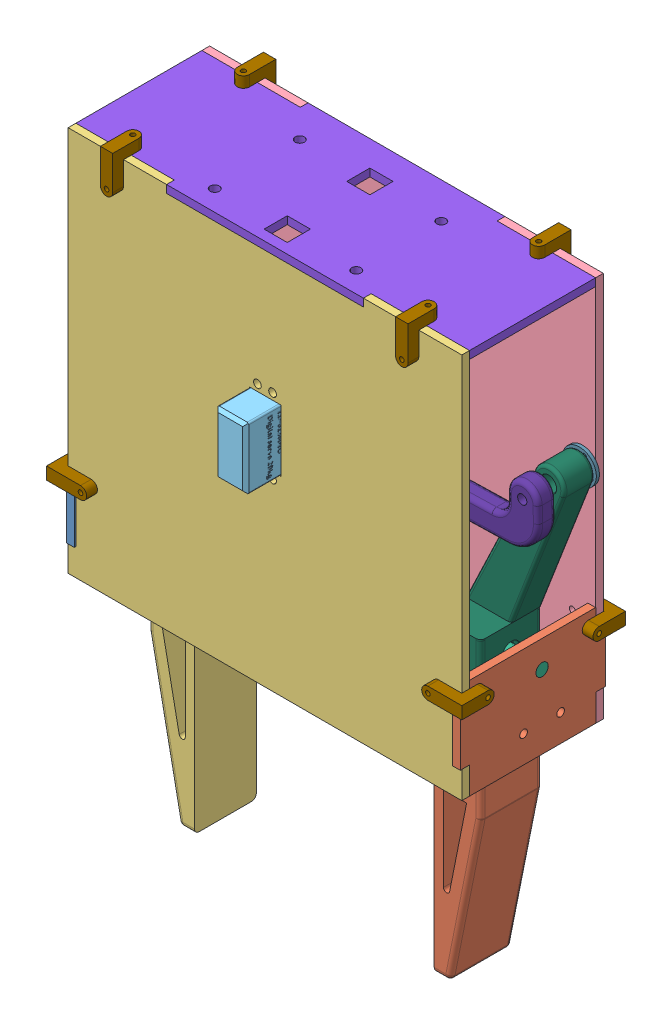
SolidWorks assembly Assem1_mica, configuration AltPosition_Default_1. Lengths in mm.
Overall size (292.18 394.5 121.5).
34 component instances, 21 part files, 82 mates.
Components (placement in the parent):
- Part2_mica-1: Part2_mica [Default] at (-23.3552 62.664 78.9474) x (0 0 -1) z (1 0 0)
- Part2_mica - Copy-1: Part2_mica - Copy [Default] at (231.6448 127.664 78.9474) x (0 0 -1) z (-1 0 0)
- Part1_mica-2: Part1_mica [Default] at (106.6448 187.664 100.9474)
- Part3_mica-1: Part3_mica [Default] at (-23.3552 127.664 19.3097) x (1 0 0) z (0 1 0)
- Servo 20 kg.stp-1: Servo 20 kg.stp [Default] at (114.1448 225.964 128.4474) x (1 0 0) z (0 1 0)
- Part3 - Copy-2: Part3 - Copy [Default] at (-18.3552 110.164 53.9474) x (1 0 0) z (0 -0.904123 0.427272)
- Part3-2: Part3 [Default] at (-23.3552 80.164 53.9474) x (1 0 0) z (0 0.470597 0.882348)
- Part4-1: Part4 [Default] at (-23.3552 307.664 100.9474) x (1 0 0) z (0 1 0)
- Part6-1: Part6 [Default] at (199.7698 312.664 14.3097) x (-1 0 0) z (0 0 -1)
- Part6-2: Part6 [Default] at (199.7698 312.664 105.9474)
- Part6-3: Part6 [Default] at (8.5198 312.664 14.3097) x (-1 0 0) z (0 0 -1)
- Part6-4: Part6 [Default] at (-23.3552 118.914 14.8917) x (0 -1 0) z (0 0 -1)
- Part6-5: Part6 [Default] at (-23.3552 118.914 105.9474) x (0 1 0) z (0 0 1)
- Part6-6: Part6 [Default] at (231.6448 118.914 13.9474) x (0 1 0) z (0 0 -1)
- Part6-7: Part6 [Default] at (231.6448 118.914 105.9474) x (0 -1 0) z (0 0 1)
- Part6-8: Part6 [Default] at (8.5198 312.664 105.9474)
- Part1-4: Part1 [Default] at (104.1448 216.164 83.9474) x (0.997708 -0.067666 0) z (0 0 -1)
- Part2 - Copy-2: Part2 - Copy [Default] at (226.6448 80.164 53.9474) x (0 0 -1) z (0 1 0) size (32 13 32)
- Part2-2: Part2 [Default] at (-18.3552 110.164 53.8656) x (0 -1 0) z (0 0 1) size (32 13 32)
- o-bi-1: o-bi [Default] at (235.7799 216.1762 62.9474) x (1 0 0) z (0 1 0) size (10 4 10)
- mat-bich-m3-1: mat-bich-m3 [Default] at (140.3117 213.7111 82.9474) x (0.997708 -0.067666 0) z (0.067666 0.997708 0) size (22 12 22)
- Part1.left - p1-2: Part1.left - p1 [Default] at (181.7677 50.164 53.9474) x (0 0 -1) z (0 1 0) size (40 64.01 185.34)
- Part1.right - p1-2: Part1.right - p1 [Default] at (26.5216 50.164 53.9474) x (0 0 1) z (0 1 0) size (40 64.01 184.7)
- Part4-3-2: Part4-3 [Default] at (235.7799 216.1762 70.9474) x (0.999667 0.025812 0) z (-0.025812 0.999667 0) size (115.5 12 40)
- Part4-3 - Copy-2: Part4-3 - Copy [Default] at (-27.4906 216.164 70.9474) x (-0.99967 -0.025685 0) z (0.025685 -0.99967 0) size (115.5 12 40)
- Part5-3: Part5 [Default] at (104.1448 216.164 80.9474) x (0.997708 -0.067666 0) z (0.067666 0.997708 0) size (92.5 10 20)
- Part1.left - p2-2: Part1.left - p2 [Default] at (181.7677 50.164 53.9474) x (0 0 -1) z (0 1 0) size (40 30 135.68)
- Part1.right - p2-2: Part1.right - p2 [Default] at (26.5216 50.164 53.9474) x (0 0 1) z (0 1 0) size (40 30 136.3)
- mat-bich-m3-2: mat-bich-m3 [Default] at (67.9779 218.6169 82.9474) x (-0.067666 -0.997708 0) z (0.997708 -0.067666 0) size (22 12 22)
- mat-bich-m3-3: mat-bich-m3 [Default] at (-27.4906 216.164 31.9474) x (0.918432 0.395578 0) z (0.395578 -0.918432 0) size (22 12 22)
- mat-bich-m3-4: mat-bich-m3 [Default] at (235.7799 216.1762 31.9474) x (0.395534 0.918452 0) z (0.918452 -0.395534 0) size (22 12 22)
- o-bi-2: o-bi [Default] at (140.3117 213.7111 67.9474) x (0.999998 0.001806 0) z (-0.001806 0.999998 0) size (10 4 10)
- o-bi-3: o-bi [Default] at (67.9779 218.6169 67.9474) x (0.530748 -0.84753 0) z (0.84753 0.530748 0) size (10 4 10)
- o-bi-4: o-bi [Default] at (-27.4906 216.164 62.9474) x (1 0 0) z (0 1 0) size (10 4 10)
Mates (geometry in assembly coordinates):
- Coincident4: coincident anti-aligned: plane of Part2_mica - Copy-1 through (226.6448 127.664 78.9474) normal (-1 0 0); plane of Part1_mica-2 through (226.6448 110.164 110.9474) normal (1 0 0)
- Coincident7: coincident anti-aligned: plane of Part2_mica - Copy-1 through (296.6525 62.664 100.9474) normal (0 0 1); plane of Part1_mica-2 through (106.6448 187.664 100.9474) normal (0 0 -1)
- Coincident10: coincident anti-aligned: plane of Part2_mica-1 through (-18.3552 62.664 78.9474) normal (1 0 0); plane of Part1_mica-2 through (-18.3552 187.664 110.9474) normal (-1 0 0)
- Coincident11: coincident aligned: plane of Part2_mica-1 through (-18.3552 62.664 78.9474) normal (0 -1 0); plane of Part1_mica-2 through (-23.3552 62.664 105.9474) normal (0 -1 0)
- Coincident12: coincident anti-aligned: plane of Part2_mica-1 through (46.6525 127.664 100.9474) normal (0 0 1); plane of Part1_mica-2 through (106.6448 187.664 100.9474) normal (0 0 -1)
- Concentric15: concentric aligned: cylinder of Part1_mica-2 through (109.0448 230.264 123.9474) axis (0 0 -1) radius 2.5; cylinder of Servo 20 kg.stp-1 through (109.0448 230.264 100.9474) axis (0 0 -1) radius 2.5
- Concentric16: concentric aligned: cylinder of Part1_mica-2 through (99.2448 230.264 123.9474) axis (0 0 -1) radius 2.5; cylinder of Servo 20 kg.stp-1 through (99.2448 230.264 100.9474) axis (0 0 -1) radius 2.5
- Coincident19: coincident anti-aligned: plane of Part1_mica-2 through (106.6448 187.664 100.9474) normal (0 0 -1); plane of Servo 20 kg.stp-1 through (104.1448 229.589 100.9474) normal (0 0 1)
- Coincident21: coincident anti-aligned: plane of Part2_mica - Copy-1 through (226.6448 127.664 78.9474) normal (-1 0 0); plane of Part3_mica-1 through (226.6448 110.164 24.3097) normal (1 0 0)
- Coincident24: coincident anti-aligned: plane of Part3_mica-1 through (104.1448 307.664 199.3097) normal (0 1 0); plane of Part4-1 through (-23.3552 307.664 100.9474) normal (0 -1 0)
- Coincident25: coincident anti-aligned: plane of Part1_mica-2 through (106.6448 187.664 100.9474) normal (0 0 -1); plane of Part4-1 through (-23.3552 312.664 100.9474) normal (0 0 1)
- Coincident26: coincident anti-aligned: plane of Part3_mica-1 through (40.3948 307.664 199.3097) normal (1 0 0); plane of Part4-1 through (40.3948 312.664 100.9474) normal (-1 0 0)
- Coincident27: coincident anti-aligned: plane of Servo 20 kg.stp-1 through (104.1448 216.164 86.9474) normal (0 0 -1); plane of Part1-4 through (104.1448 216.164 86.9474) normal (0 0 1)
- Concentric36: concentric aligned: cylinder of Servo 20 kg.stp-1 through (104.1448 216.164 86.9474) axis (0 0 -1) radius 3; cylinder of Part1-4 through (104.1448 216.164 86.9474) axis (0 0 -1) radius 3
- Coincident34: coincident anti-aligned: plane of Part1_mica-2 through (104.1448 307.664 285.9474) normal (0 1 0); plane of Part4-1 through (-23.3552 307.664 100.9474) normal (0 -1 0)
- Concentric60: concentric aligned: cylinder of Part4-1 through (8.5198 317.664 24.3097) axis (0 -1 0) radius 2; cylinder of Part6-3 through (8.5198 319.664 24.3097) axis (0 -1 0) radius 1.5
- Concentric61: concentric aligned: cylinder of Part4-1 through (199.7698 317.664 24.3097) axis (0 -1 0) radius 2; cylinder of Part6-1 through (199.7698 319.664 24.3097) axis (0 -1 0) radius 1.5
- Concentric62: concentric anti-aligned: cylinder of Part3_mica-1 through (199.7698 297.664 24.3097) axis (0 0 -1) radius 2; cylinder of Part6-1 through (199.7698 297.664 7.3097) axis (0 0 1) radius 1.5
- Coincident35: coincident anti-aligned: plane of Part3_mica-1 through (-23.3552 127.664 19.3097) normal (0 0 1); plane of Part4-1 through (-23.3552 307.664 19.3097) normal (0 0 -1)
- Concentric63: concentric anti-aligned: cylinder of Part3_mica-1 through (8.5198 297.664 24.3097) axis (0 0 -1) radius 2; cylinder of Part6-3 through (8.5198 297.664 7.3097) axis (0 0 1) radius 1.5
- Concentric64: concentric aligned: cylinder of Part4-1 through (8.5198 317.664 95.9474) axis (0 -1 0) radius 2; cylinder of Part6-8 through (8.5198 319.664 95.9474) axis (0 -1 0) radius 1.5
- Concentric65: concentric aligned: cylinder of Part1_mica-2 through (8.5198 297.664 110.9474) axis (0 0 -1) radius 2; cylinder of Part6-8 through (8.5198 297.664 112.9474) axis (0 0 -1) radius 1.5
- Concentric66: concentric aligned: cylinder of Part4-1 through (199.7698 317.664 95.9474) axis (0 -1 0) radius 2; cylinder of Part6-2 through (199.7698 319.664 95.9474) axis (0 -1 0) radius 1.5
- Concentric67: concentric aligned: cylinder of Part1_mica-2 through (199.7698 297.664 110.9474) axis (0 0 -1) radius 2; cylinder of Part6-2 through (199.7698 297.664 112.9474) axis (0 0 -1) radius 1.5
- Concentric68: concentric aligned: cylinder of Part2_mica-1 through (-28.3552 118.914 95.9474) axis (1 0 0) radius 2; cylinder of Part6-5 through (-30.3552 118.914 95.9474) axis (1 0 0) radius 1.5
- Concentric69: concentric aligned: cylinder of Part1_mica-2 through (-8.3552 118.914 110.9474) axis (0 0 -1) radius 2; cylinder of Part6-5 through (-8.3552 118.914 112.9474) axis (0 0 -1) radius 1.5
- Concentric70: concentric aligned: cylinder of Part2_mica-1 through (-28.3552 118.914 24.8917) axis (1 0 0) radius 2; cylinder of Part6-4 through (-30.3552 118.914 24.8917) axis (1 0 0) radius 1.5
- Concentric71: concentric anti-aligned: cylinder of Part3_mica-1 through (-8.3552 118.914 24.3097) axis (0 0 -1) radius 2; cylinder of Part6-4 through (-8.3552 118.914 7.8917) axis (0 0 1) radius 1.5
- Concentric72: concentric anti-aligned: cylinder of Part3_mica-1 through (216.6448 118.914 24.3097) axis (0 0 -1) radius 2; cylinder of Part6-6 through (216.6448 118.914 6.9474) axis (0 0 1) radius 1.5
- Concentric73: concentric aligned: cylinder of Part2_mica - Copy-1 through (236.6448 118.914 23.9474) axis (-1 0 0) radius 2; cylinder of Part6-6 through (238.6448 118.914 23.9474) axis (-1 0 0) radius 1.5
- Concentric74: concentric aligned: cylinder of Part1_mica-2 through (216.6448 118.914 110.9474) axis (0 0 -1) radius 2; cylinder of Part6-7 through (216.6448 118.914 112.9474) axis (0 0 -1) radius 1.5
- Concentric75: concentric aligned: cylinder of Part2_mica - Copy-1 through (236.6448 118.914 95.9474) axis (-1 0 0) radius 2; cylinder of Part6-7 through (238.6448 118.914 95.9474) axis (-1 0 0) radius 1.5
- Concentric84: concentric anti-aligned: cylinder of Part2_mica - Copy-1 through (236.6448 80.164 41.9474) axis (-1 0 0) radius 2.5; cylinder of Part2 - Copy-2 through (223.6448 80.164 41.9474) axis (1 0 0) radius 2
- Concentric85: concentric anti-aligned: cylinder of Part2_mica - Copy-1 through (236.6448 80.164 65.9474) axis (-1 0 0) radius 2.5; cylinder of Part2 - Copy-2 through (223.6448 80.164 65.9474) axis (1 0 0) radius 2
- Coincident37: coincident anti-aligned: plane of Part2_mica - Copy-1 through (226.6448 127.664 78.9474) normal (-1 0 0); plane of Part2 - Copy-2 through (226.6448 80.164 53.9474) normal (1 0 0)
- Concentric86: concentric aligned: cylinder of Part2_mica-1 through (-28.3552 110.164 65.8656) axis (1 0 0) radius 2.5; cylinder of Part2-2 through (-74.3552 110.164 65.8656) axis (1 0 0) radius 2
- Concentric87: concentric anti-aligned: cylinder of Part2_mica-1 through (-28.3552 110.164 41.8656) axis (1 0 0) radius 2.5; cylinder of Part2-2 through (-15.3552 110.164 41.8656) axis (-1 0 0) radius 2
- Coincident38: coincident anti-aligned: plane of Part2_mica-1 through (-18.3552 62.664 78.9474) normal (1 0 0); plane of Part2-2 through (-18.3552 110.164 53.8656) normal (-1 0 0)
- Coincident39: coincident anti-aligned: plane of Part2_mica-1 through (-18.3552 62.664 78.9474) normal (1 0 0); plane of Part3 - Copy-2 through (-18.3552 110.164 53.9474) normal (-1 0 0)
- Parallel7: parallel anti-aligned: cylinder of Part2_mica - Copy-1 through (226.6448 110.164 53.9474) axis (1 0 0) radius 4; cylinder of Part3 - Copy-2 through (231.6448 110.164 53.9474) axis (-1 0 0) radius 4
- Concentric93: concentric anti-aligned: cylinder of Part2_mica - Copy-1 through (226.6448 110.164 53.9474) axis (1 0 0) radius 4; cylinder of Part3 - Copy-2 through (231.6448 110.164 53.9474) axis (-1 0 0) radius 4
- Concentric99: concentric anti-aligned: cylinder of Part1-4 through (97.1609 216.6377 80.9474) axis (0 0 1) radius 1.5; cylinder of Part5-3 through (97.1609 216.6377 80.9474) axis (0 0 -1) radius 2
- Concentric100: concentric anti-aligned: cylinder of Part1-4 through (111.1288 215.6904 80.9474) axis (0 0 1) radius 1.5; cylinder of Part5-3 through (111.1288 215.6904 80.9474) axis (0 0 -1) radius 2
- Coincident41: coincident anti-aligned: plane of Part1-4 through (104.1448 216.164 80.9474) normal (0 0 -1); plane of Part5-3 through (104.1448 216.164 80.9474) normal (0 0 1)
- Concentric101: concentric anti-aligned: cylinder of mat-bich-m3-1 through (140.3117 213.7111 70.9474) axis (0 0 1) radius 5; cylinder of Part5-3 through (140.3117 213.7111 80.9474) axis (0 0 -1) radius 5.25
- Concentric102: concentric anti-aligned: cylinder of mat-bich-m3-1 through (132.3301 214.2525 80.9474) axis (0 0 1) radius 1.5; cylinder of Part5-3 through (132.3301 214.2525 80.9474) axis (0 0 -1) radius 1.45
- Coincident42: coincident anti-aligned: plane of mat-bich-m3-1 through (140.3117 213.7111 80.9474) normal (0 0 -1); plane of Part5-3 through (104.1448 216.164 80.9474) normal (0 0 1)
- Concentric103: concentric anti-aligned: cylinder of Part5-3 through (67.9779 218.6169 80.9474) axis (0 0 -1) radius 5.25; cylinder of mat-bich-m3-2 through (67.9779 218.6169 70.9474) axis (0 0 1) radius 5
- Concentric104: concentric anti-aligned: cylinder of Part5-3 through (75.9596 218.0756 80.9474) axis (0 0 -1) radius 1.45; cylinder of mat-bich-m3-2 through (75.9596 218.0756 80.9474) axis (0 0 1) radius 1.5
- Coincident43: coincident anti-aligned: plane of Part5-3 through (104.1448 216.164 80.9474) normal (0 0 1); plane of mat-bich-m3-2 through (67.9779 218.6169 80.9474) normal (0 0 -1)
- Concentric105: concentric aligned: cylinder of Part3 - Copy-2 through (231.6448 110.164 53.9474) axis (-1 0 0) radius 4; cylinder of Part1.left - p1-2 through (228.688 110.164 53.9474) axis (-1 0 0) radius 7.75
- Concentric107: concentric anti-aligned: cylinder of Part3-2 through (226.6448 80.164 53.9474) axis (-1 0 0) radius 4; cylinder of Part2 - Copy-2 through (213.6448 80.164 53.9474) axis (1 0 0) radius 4
- Coincident44: coincident aligned: plane of Part2_mica-1 through (-23.3552 62.664 78.9474) normal (-1 0 0); plane of Part3-2 through (-23.3552 80.164 53.9474) normal (-1 0 0)
- Concentric108: concentric anti-aligned: cylinder of Part3-2 through (226.6448 80.164 53.9474) axis (-1 0 0) radius 4; cylinder of Part1.left - p1-2 through (206.7677 80.164 53.9474) axis (1 0 0) radius 6
- Concentric109: concentric aligned: cylinder of Part3 - Copy-2 through (231.6448 110.164 53.9474) axis (-1 0 0) radius 4; cylinder of Part1.right - p1-2 through (1.5216 110.164 53.9474) axis (-1 0 0) radius 6
- Concentric110: concentric aligned: cylinder of Part3-2 through (226.6448 80.164 53.9474) axis (-1 0 0) radius 4; cylinder of Part1.right - p1-2 through (1.5216 80.164 53.9474) axis (-1 0 0) radius 6
- Coincident45: coincident aligned: plane of Part1.left - p1-2 through (211.7677 125.164 33.9474) normal (0 0 -1); plane of Part1.left - p2-2 through (211.7677 125.164 33.9474) normal (0 0 -1)
- Coincident46: coincident anti-aligned: plane of Part1.left - p1-2 through (181.7677 40.8412 82.9474) normal (0 -1 0); plane of Part1.left - p2-2 through (181.7677 40.8412 77.9474) normal (0 1 0)
- Coincident47: coincident anti-aligned: plane of Part1.left - p1-2 through (196.7677 50.164 82.9474) normal (1 0 0); plane of Part1.left - p2-2 through (196.7677 50.164 77.9474) normal (-1 0 0)
- Coincident49: coincident anti-aligned: plane of Part1.right - p1-2 through (26.5216 41.4611 24.9474) normal (0 -1 0); plane of Part1.right - p2-2 through (26.5216 41.4611 32.9474) normal (0 1 0)
- Coincident50: coincident anti-aligned: plane of Part1.right - p1-2 through (11.5216 50.164 24.9474) normal (-1 0 0); plane of Part1.right - p2-2 through (11.5216 50.164 32.9474) normal (1 0 0)
- Coincident52: coincident aligned: plane of Part1.right - p1-2 through (-3.4784 125.164 33.9474) normal (0 0 -1); plane of Part1.right - p2-2 through (-3.4784 125.164 33.9474) normal (0 0 -1)
- Concentric111: concentric aligned: cylinder of Part1.left - p1-2 through (235.7799 216.1762 68.9474) axis (0 0 -1) radius 5.25; cylinder of mat-bich-m3-4 through (235.7799 216.1762 43.9474) axis (0 0 -1) radius 5
- Concentric112: concentric aligned: cylinder of Part1.left - p1-2 through (232.6156 208.8286 55.9474) axis (0 0 -1) radius 1.45; cylinder of mat-bich-m3-4 through (232.6156 208.8286 33.9474) axis (0 0 -1) radius 1.5
- Coincident53: coincident anti-aligned: plane of Part1.left - p1-2 through (211.7677 125.164 33.9474) normal (0 0 -1); plane of mat-bich-m3-4 through (235.7799 216.1762 33.9474) normal (0 0 1)
- Concentric113: concentric aligned: cylinder of Part1.right - p1-2 through (-27.4906 216.164 67.9474) axis (0 0 -1) radius 5.25; cylinder of mat-bich-m3-3 through (-27.4906 216.164 43.9474) axis (0 0 -1) radius 5
- Concentric114: concentric aligned: cylinder of Part1.right - p1-2 through (-24.326 208.8166 54.9474) axis (0 0 -1) radius 1.45; cylinder of mat-bich-m3-3 through (-24.326 208.8166 33.9474) axis (0 0 -1) radius 1.5
- Coincident54: coincident anti-aligned: plane of Part1.right - p1-2 through (-3.4784 125.164 33.9474) normal (0 0 -1); plane of mat-bich-m3-3 through (-27.4906 216.164 33.9474) normal (0 0 1)
- Concentric115: concentric aligned: cylinder of Part4-3-2 through (140.3117 213.7111 34.9474) axis (0 0 1) radius 5.25; cylinder of o-bi-2 through (140.3117 213.7111 63.9474) axis (0 0 1) radius 5
- Concentric116: concentric anti-aligned: circle of o-bi-1; circle of Part4-3-2
- Coincident56: coincident aligned: plane of o-bi-1 through (235.7799 216.1762 58.9474) normal (0 0 -1); plane of Part4-3-2 through (235.7799 216.1762 58.9474) normal (0 0 -1)
- Concentric117: concentric aligned: cylinder of Part4-3 - Copy-2 through (-27.4906 216.164 45.9474) axis (0 0 1) radius 5.25; cylinder of o-bi-4 through (-27.4906 216.164 58.9474) axis (0 0 1) radius 5
- Coincident57: coincident aligned: plane of Part4-3 - Copy-2 through (-27.4906 216.164 58.9474) normal (0 0 -1); plane of o-bi-4 through (-27.4906 216.164 58.9474) normal (0 0 -1)
- Concentric118: concentric aligned: cylinder of Part4-3 - Copy-2 through (67.9779 218.6169 45.9474) axis (0 0 1) radius 5.25; cylinder of o-bi-3 through (67.9779 218.6169 63.9474) axis (0 0 1) radius 5
- Concentric119: concentric anti-aligned: cylinder of mat-bich-m3-1 through (140.3117 213.7111 80.9474) axis (0 0 -1) radius 1.5; cylinder of o-bi-2 through (140.3117 213.7111 63.9474) axis (0 0 1) radius 1.5
- Concentric120: concentric anti-aligned: cylinder of o-bi-1 through (235.7799 216.1762 58.9474) axis (0 0 1) radius 1.5; cylinder of Part1.left - p1-2 through (235.7799 216.1762 68.9474) axis (0 0 -1) radius 5.25
- Concentric123: concentric aligned: circle of mat-bich-m3-3; cylinder of o-bi-4 through (-27.4906 216.164 58.9474) axis (0 0 1) radius 1.5
- Concentric126: concentric aligned: cylinder of mat-bich-m3-2 through (67.9779 218.6169 80.9474) axis (0 0 -1) radius 1.5; circle of o-bi-3
- Coincident64: coincident anti-aligned: plane of Part4-3-2 through (140.3117 213.7111 63.9474) normal (0 0 1); plane of o-bi-2 through (140.3117 213.7111 63.9474) normal (0 0 -1)
- Coincident66: coincident anti-aligned: plane of Part4-3 - Copy-2 through (67.9779 218.6169 63.9474) normal (0 0 1); plane of o-bi-3 through (67.9779 218.6169 63.9474) normal (0 0 -1)
- Coincident67: coincident anti-aligned: plane of Part4-3 - Copy-2 through (-27.4906 216.164 70.9474) normal (0 0 1); plane of Part5-3 through (104.1448 216.164 70.9474) normal (0 0 -1)
- Coincident68: coincident anti-aligned: plane of Part4-3-2 through (235.7799 216.1762 70.9474) normal (0 0 1); plane of Part5-3 through (104.1448 216.164 70.9474) normal (0 0 -1)
